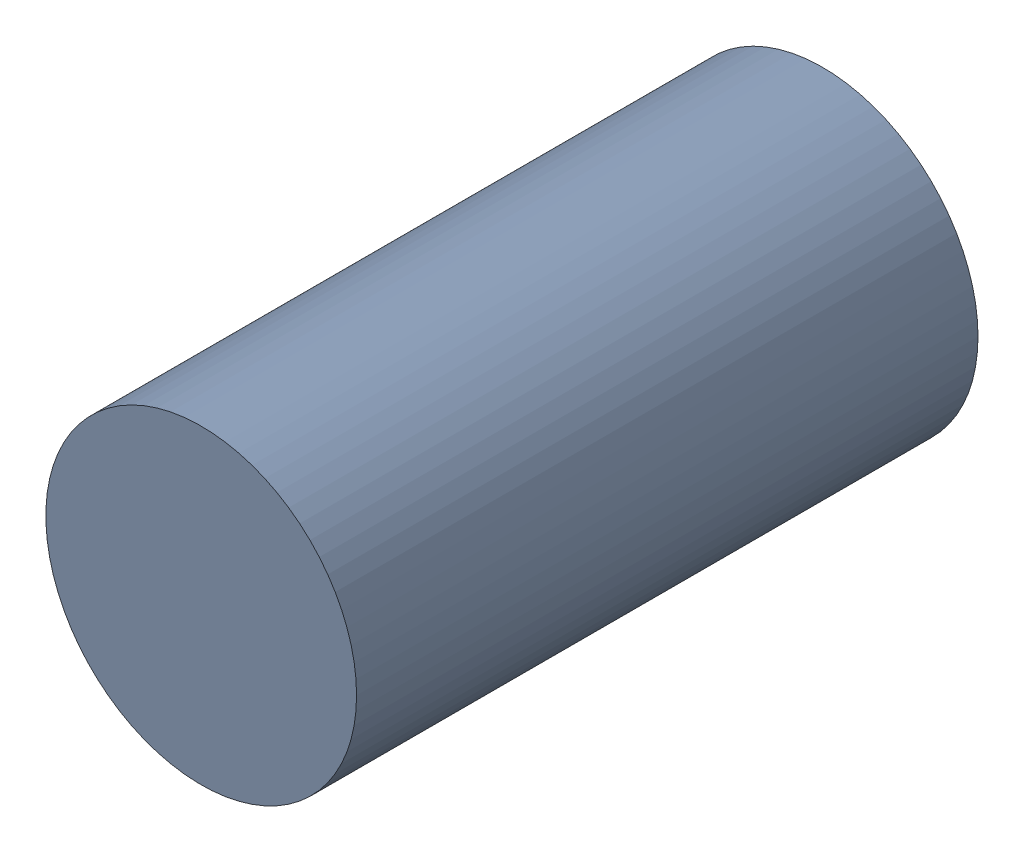
SolidWorks assembly MH8_1.step, configuration Default. Lengths in mm.
Overall size (1 1 2).
2 component instances, 1 part files, 0 mates.
Components (placement in the parent):
- 9228463120_1.step-11: 9228463120_1.step [Default] at (453.1617 244.3607 -1.5) size (1 1 2)
  - Cylinder_1.step-98: Cylinder_1.step [Default] at origin size (1 1 2)
